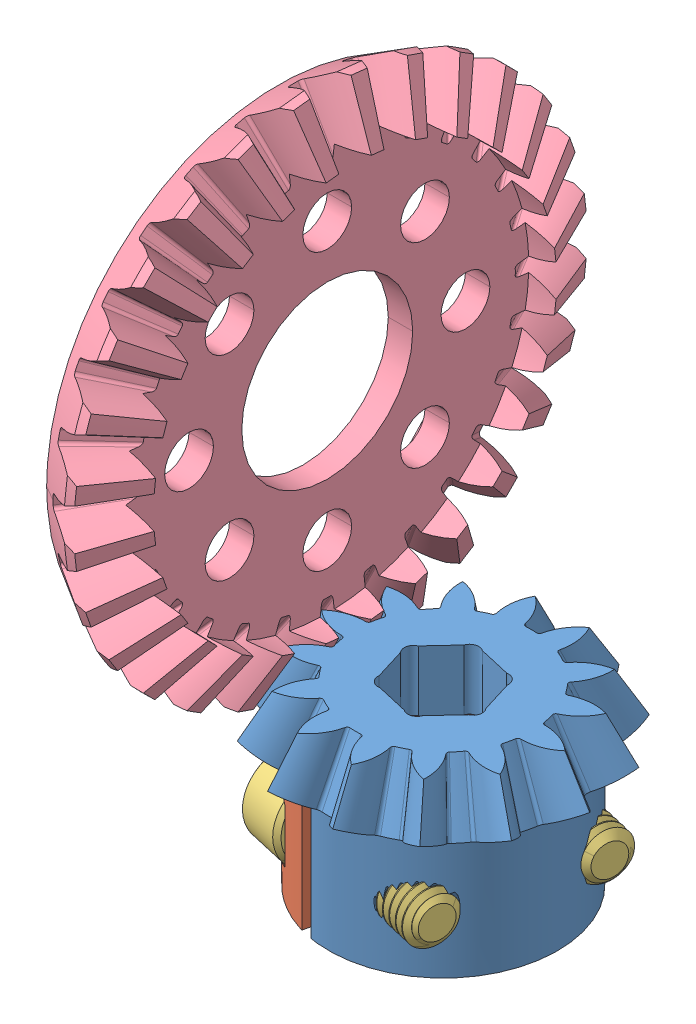
SolidWorks assembly 3204-0002-0002 2 to 1 bevel gears, configuration Default. Lengths in mm.
Overall size (28.77 52.38 42.6).
6 component instances, 4 part files, 0 mates.
Components (placement in the parent):
- 2306-4008-0014 assembly.STEP-1: 2306-4008-0014 assembly.STEP [Default] at (-86.5036 -22.1715 14.0673) x (0 1 0) z (-0.223733 0 0.97465) size (15.4 23.91 24.42)
  - 2306-4008-0014.STEP-1: 2306-4008-0014.STEP [Default] at (-4.2928 -28.4802 22.5212) size (15.33 23.91 24.42)
  - 2306-4008-0014 clamp.STEP-1: 2306-4008-0014 clamp.STEP [Default] at (-4.2932 -28.4802 22.5212) size (9.55 8.86 18.69)
  - 2800-0004-0012_90128A207.STEP-1: 2800-0004-0012_90128A207.STEP [Default] at (-8.9015 -37.2302 16.6212) x (0.549526 0 0.835476) z (0 -1 0) size (7 7 16.01)
  - 2800-0004-0012_90128A207.STEP-2: 2800-0004-0012_90128A207.STEP [Default] at (-8.9015 -37.2302 28.4212) x (0.549526 0 -0.835476) z (0 -1 0) size (7 7 16.01)
- 2307-0014-0028.STEP-1: 2307-0014-0028.STEP [Default] at (-76.6728 -4.8452 42.3896) size (6.38 42.6 42.6)
